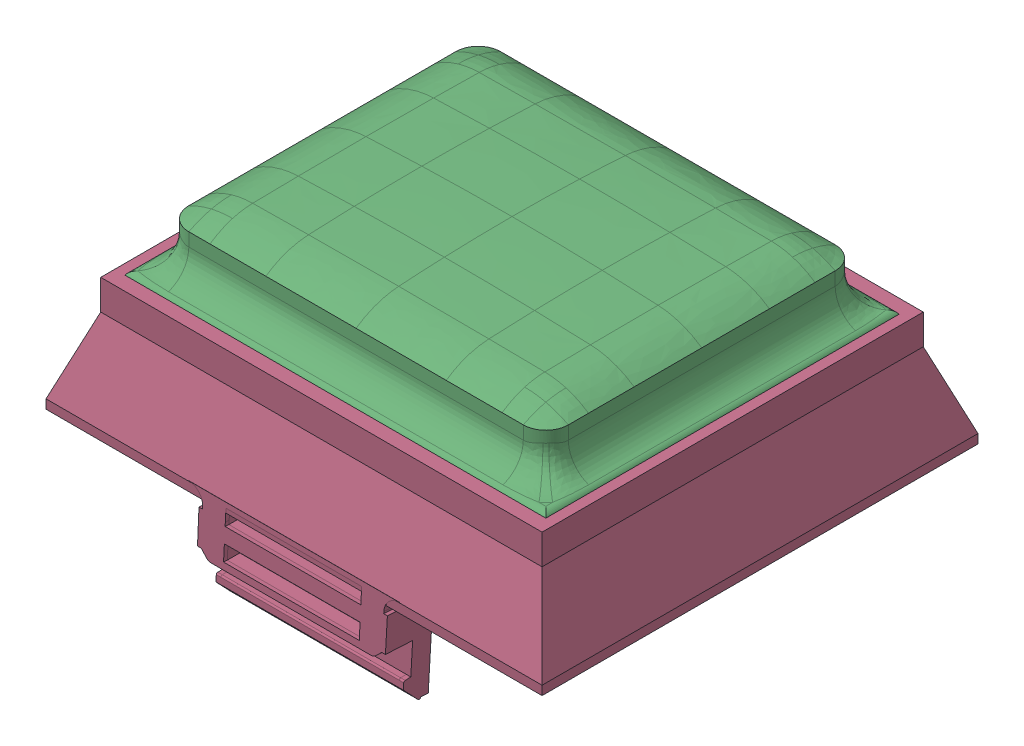
SolidWorks assembly Coord, configuration 默认. Lengths in mm.
Overall size (33 18.27 29.5).
5 component instances, 5 part files, 12 mates.
Components (placement in the parent):
- Coordlensall-1: Coordlensall [默认] at origin size (28.33 2.18 23.83)
- CoordInsideSkin1 (1)-1: CoordInsideSkin1 (1) [默认] at (0.0001 0 0.2499) size (23.8 5.48 19.29)
- CoordTopskin-1: CoordTopskin [默认] at (0.0001 2 0.2499) size (28.02 6.25 23.52)
- CoordSupportBase-2: CoordSupportBase [默认] at origin size (33 14.02 29.5)
- CoordinateMarker-1: CoordinateMarker [默认] at (-1.2748 23.7 0.6861) x (1 0 0) z (0 -1 0) size (23.6 17.6 1.5)
Mates (geometry in assembly coordinates):
- 同心2: concentric anti-aligned: cylinder of CoordInsideSkin1 (1)-1 through (10.8751 17.7531 8.6249) axis (0 1 0) radius 0.7; cylinder of Board3Con1612611OriginalSkin_TOP-1 through (10.8751 24 8.6249) axis (0 -1 0) radius 0.7
- 同心3: concentric anti-aligned: cylinder of CoordInsideSkin1 (1)-1 through (10.8751 17.7531 -9.1251) axis (0 1 0) radius 0.7; cylinder of Board3Con1612611OriginalSkin_TOP-1 through (10.8751 24 -9.1251) axis (0 -1 0) radius 0.7
- 重合4: coincident aligned: plane of CoordInsideSkin1 (1)-1 through (10.8751 19 -9.1251) normal (0 -1 0); plane of Board3Con1612611OriginalSkin_TOP-1 through (0.0001 19 0.2499) normal (0 -1 0)
- 重合6: coordinate: point of CoordSupportBase-2
- 重合7: coincident anti-aligned: plane of lensall-1 through (13.75 19 -11.5) normal (0.939693 0.34202 0); plane of CoordSupportBase-2 through (13.75 19 12.7803) normal (-0.939693 -0.34202 0)
- 同心5: concentric aligned: cylinder of lensall-1 through (13.3294 18.6938 -11.0794) axis (-0.323616 0.889126 0.323616) radius 0.5; cylinder of CoordSupportBase-2 through (10.7866 25.6801 -8.5366) axis (-0.323616 0.889126 0.323616) radius 0.5
- 重合8: coincident anti-aligned: plane of lensall-1 through (0 18 0) normal (0 -1 0); plane of CoordSupportBase-2 through (0 18 0) normal (0 1 0)
- 重合9: coincident anti-aligned: plane of lensall-1 through (0 19 0) normal (0 1 0); plane of Board3Con1612611OriginalSkin_TOP-1 through (0.0001 19 0.2499) normal (0 -1 0)
- 重合10: coincident anti-aligned: plane of Board3Con1612611OriginalSkin_TOP-1 through (0.0001 19 11.7499) normal (0 0 1); plane of CoordSupportBase-2 through (-13.5999 21 11.7499) normal (0 0 -1)
- 重合11: coincident anti-aligned: plane of Board3Con1612611OriginalSkin_TOP-1 through (14.0001 19 0.2499) normal (1 0 0); plane of CoordSupportBase-2 through (14.0001 21 11.7499) normal (-1 0 0)
- 宽度1: width aligned: plane of CoordInsideSkin1 (1)-1 through (11.5751 17.7531 -9.1251) normal (1 0 0); plane of CoordinateMarker-1 through (-12.0749 17.7531 -9.1251) normal (-1 0 0); plane of CoordInsideSkin1 (1)-1 through (11.5501 22.95 -8.2501) normal (1 0 0); plane of CoordinateMarker-1 through (-12.0499 22.95 -8.2501) normal (-1 0 0)
- 重合12: coincident aligned: circle of CoordInsideSkin1 (1)-1; circle of CoordinateMarker-1
